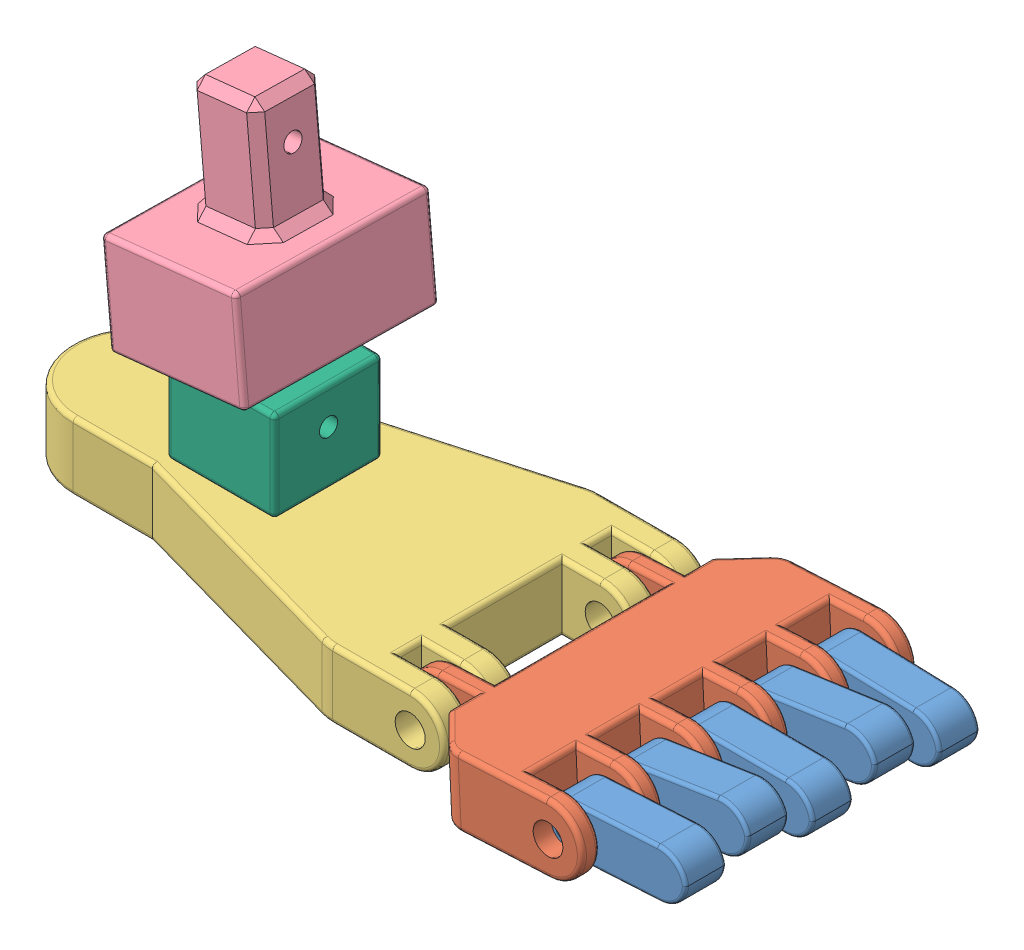
SolidWorks assembly 01_ML, configuration Default. Lengths in mm.
Overall size (217.09 125.16 115.13).
11 component instances, 6 part files, 18 mates.
Components (placement in the parent):
- 01_01_00_01_ML-1: 01_01_00_01_ML [Default] at (91.736 64.4661 112.913) x (0.99842 0.056194 0) z (0 0 1) size (39.75 13.46 11.53)
- 01_01_00_01_ML-2: 01_01_00_01_ML [Default] at (91.736 64.4661 59.573) x (0.989807 0.142414 0) z (0 0 1) size (39.75 13.46 11.53)
- 01_01_00_01_ML-3: 01_01_00_01_ML [Default] at (91.736 64.4661 77.353) x (0.999993 -0.003664 0) z (0 0 1) size (39.75 13.46 11.53)
- 01_01_00_01_ML-4: 01_01_00_01_ML [Default] at (91.736 64.4661 95.133) x (0.988208 0.153118 0) z (0 0 1) size (39.75 13.46 11.53)
- 01_01_00_01_ML-5: 01_01_00_01_ML [Default] at (91.736 64.4661 41.793) x (0.999491 -0.031917 0) z (0 0 1) size (39.75 13.46 11.53)
- 01_01_00_02_ML-1: 01_01_00_02_ML [Default] at (91.736 64.4661 36.078) x (0.998844 0.04807 0) z (0 0 1) size (67.31 19.05 93.98)
- 01_01_00_03_ML-1: 01_01_00_03_ML [Default] at (43.5318 62.1462 45.603) size (141.61 41.91 74.93)
- 01_01_01_ML-1: 01_01_01_ML [Default] at (-25.8856 139.5681 67.3471) x (-0.883246 -0.428005 0.191543) z (0.05314 -0.497218 -0.865997) size (72.61 105.89 83.55) (flexible)
  - 01_01_01_01_ML-2: 01_01_01_01_ML [Default] at (23.9122 -31.6779 4.032) x (0.186911 -0.450738 -0.872869) z (0.923728 0.383049 0) size (54.63 59.06 38.1)
  - 01_01_01_02_ML-2: 01_01_01_02_ML [Default] at (23.9122 -31.6779 4.032) x (-0.923728 -0.383049 0) z (0.191543 -0.461909 -0.865997) size (35.56 24.14 48.26)
  - 01_01_01_03_ML-1: 01_01_01_03_ML [Default] at (23.9122 -31.6779 4.032) x (0.883246 0.46589 -0.05314) z (-0.191543 0.461909 0.865997) size (30.35 44.2 33.02)
Mates (geometry in assembly coordinates):
- Concentric8: concentric aligned: circle of 01_01_00_02_ML-1; circle of 01_01_00_01_ML-1
- Concentric10: concentric aligned: circle of 01_01_00_02_ML-1; circle of 01_01_00_01_ML-4
- Concentric12: concentric aligned: circle of 01_01_00_02_ML-1; circle of 01_01_00_01_ML-3
- Concentric13: concentric aligned: circle of 01_01_00_01_ML-3; circle of 01_01_00_02_ML-1
- Concentric14: concentric aligned: circle of 01_01_00_02_ML-1; circle of 01_01_00_01_ML-5
- Concentric15: concentric aligned: circle of 01_01_00_02_ML-1; circle of 01_01_00_01_ML-2
- Coincident10: coincident anti-aligned: plane of UpperFoot-1 through (-63.1482 62.1462 92.593) normal (0 0 1); plane of Heel-1 through (-63.1482 67.2262 92.593) normal (0 0 -1)
- Coincident11: coincident anti-aligned: plane of 01_01_00_03_ML-1 through (-47.9082 62.1462 129.423) normal (-1 0 0); plane of Heel-1 through (-47.9082 71.6712 109.738) normal (1 0 0)
- Coincident12: coincident anti-aligned: plane of UpperFoot-1 through (-63.1482 62.1462 82.433) normal (0 0 -1); plane of Heel-1 through (-63.1482 67.2262 82.433) normal (0 0 1)
- Coincident13: coincident aligned: plane of 01_01_00_03_ML-1 through (43.5318 52.6212 53.223) normal (0 -1 0); plane of Heel-1 through (-92.3582 52.6212 109.738) normal (0 -1 0)
- Concentric16: concentric aligned: circle of 01_01_00_02_ML-1; circle of 01_01_00_03_ML-1
- ProfileCenter2: profile center anti-aligned: plane of 01_01_00_03_ML-1 through (43.5318 94.5312 45.603) normal (0 1 0); plane of 01_01_01_ML-1/01_01_01_03_ML-1 through (-32.0332 94.5312 83.068) normal (0 -1 0)
- Width1: width anti-aligned: plane of 01_01_00_03_ML-1 through (43.5318 62.1462 53.223) normal (0 0 1); plane of 01_01_00_03_ML-1 through (43.5318 62.1462 59.573) normal (0 0 -1); plane of 01_01_00_02_ML-1 through (91.736 64.4661 53.858) normal (0 0 -1); plane of 01_01_00_02_ML-1 through (91.736 64.4661 58.938) normal (0 0 1)
- Width2: width aligned: plane of 01_01_00_02_ML-1 through (91.736 64.4661 41.158) normal (0 0 1); plane of 01_01_00_02_ML-1 through (91.736 64.4661 53.858) normal (0 0 -1); plane of 01_01_00_01_ML-5 through (91.736 64.4661 53.223) normal (0 0 1); plane of 01_01_00_01_ML-5 through (91.736 64.4661 41.793) normal (0 0 -1)
- Width3: width aligned: plane of 01_01_00_02_ML-1 through (91.736 64.4661 58.938) normal (0 0 1); plane of 01_01_00_02_ML-1 through (91.736 64.4661 71.638) normal (0 0 -1); plane of 01_01_00_01_ML-2 through (91.736 64.4661 71.003) normal (0 0 1); plane of 01_01_00_01_ML-2 through (91.736 64.4661 59.573) normal (0 0 -1)
- Width4: width aligned: plane of 01_01_00_02_ML-1 through (91.736 64.4661 76.718) normal (0 0 1); plane of 01_01_00_02_ML-1 through (91.736 64.4661 89.418) normal (0 0 -1); plane of 01_01_00_01_ML-3 through (91.736 64.4661 88.783) normal (0 0 1); plane of 01_01_00_01_ML-3 through (91.736 64.4661 77.353) normal (0 0 -1)
- Width5: width anti-aligned: plane of 01_01_00_02_ML-1 through (91.736 64.4661 112.278) normal (0 0 1); plane of 01_01_00_02_ML-1 through (91.736 64.4661 124.978) normal (0 0 -1); plane of 01_01_00_01_ML-1 through (91.736 64.4661 112.913) normal (0 0 -1); plane of 01_01_00_01_ML-1 through (91.736 64.4661 124.343) normal (0 0 1)
- Width6: width anti-aligned: plane of 01_01_00_02_ML-1 through (91.736 64.4661 107.198) normal (0 0 -1); plane of 01_01_00_02_ML-1 through (91.736 64.4661 94.498) normal (0 0 1); plane of 01_01_00_01_ML-4 through (91.736 64.4661 106.563) normal (0 0 1); plane of 01_01_00_01_ML-4 through (91.736 64.4661 95.133) normal (0 0 -1)
